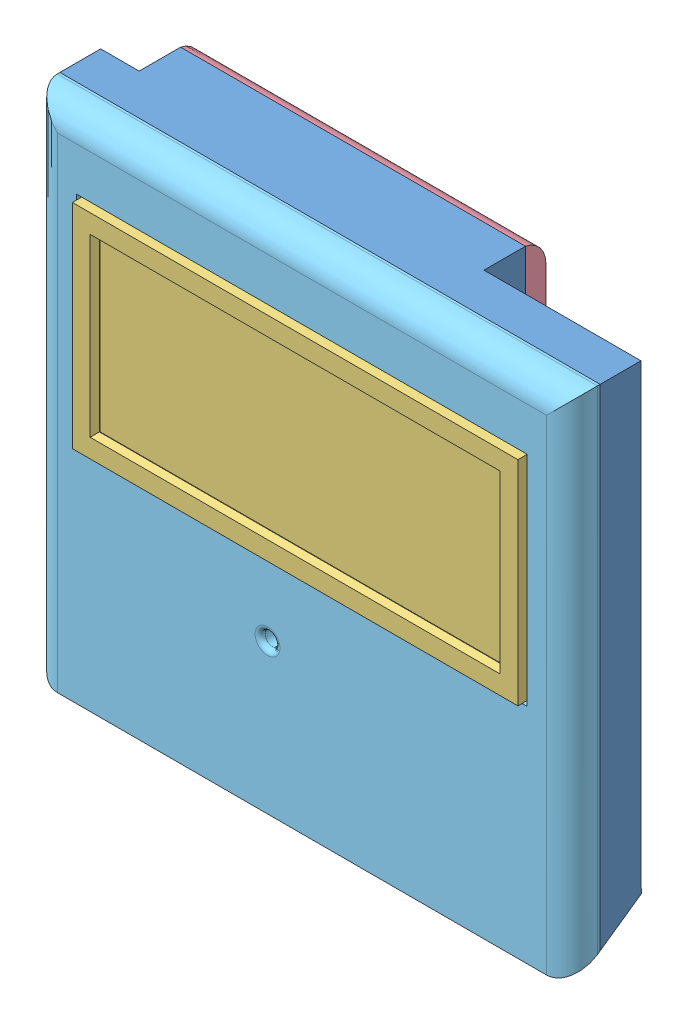
SolidWorks assembly Assem2, configuration Default. Lengths in mm.
Overall size (879.81 203.75 39.02).
7 component instances, 7 part files, 12 mates.
Components (placement in the parent):
- middle-1: middle [Default] at (-126.7138 -34.7069 38.7563) size (105.87 96.14 16.13)
- PCB-1: PCB [Default] at (-122.7138 -30.7069 38.7663) size (255.19 160.09 12.72)
- LCD-2: LCD [Default] at (-130.2538 -17.5769 50.8863) size (765.52 168.67 15.05)
- back-1: back [Default] at (-124.8566 -10.3763 34.7563) x (1 0 0) z (0 -1 0) size (68.96 18.07 84.84)
- Front-1: Front [Default] at (-97.2484 -1.8747 58.8863) x (1 0 0) z (0 1 0) size (105.87 7.85 99.99)
- ResetButton-1: ResetButton [Default] at (-122.7138 42.3331 42.2163) x (1 0 0) z (0 -1 0) size (10.17 4.88 5)
- GPS-1: GPS [Default] at (-73.4443 33.5217 42.1998) x (0 -1 0) z (0 0 1) size (34.65 8.27 6.52)
Mates (geometry in assembly coordinates):
- Coincident2: coincident anti-aligned: plane of middle-1 through (-126.7138 -34.7069 40.3863) normal (0 0 -1); plane of PCB-1 through (-122.7138 -30.7069 40.3863) normal (0 0 1)
- Coincident3: coincident anti-aligned: plane of middle-1 through (-122.7138 43.3331 50.8863) normal (0 -1 0); plane of PCB-1 through (-122.7138 43.3331 40.3863) normal (0 1 0)
- Coincident4: coincident anti-aligned: plane of middle-1 through (-63.1438 43.3331 50.8863) normal (-1 0 0); plane of PCB-1 through (-63.1438 -30.7069 40.3863) normal (1 0 0)
- Coincident8: coincident aligned: plane of PCB-1 through (-81.2138 41.1631 47.9263) normal (0 1 0); plane of LCD-2 through (-81.2138 41.1631 48.3363) normal (0 1 0)
- Coincident9: coincident aligned: plane of PCB-1 through (-81.2138 41.1631 47.9263) normal (1 0 0); plane of LCD-2 through (-81.2138 41.1631 48.3363) normal (1 0 0)
- Coincident10: coincident anti-aligned: plane of middle-1 through (-126.7138 -34.7069 50.8863) normal (0 0 1); plane of LCD-2 through (-130.2538 -17.5769 50.8863) normal (0 0 -1)
- Coincident12: coincident anti-aligned: plane of middle-1 through (-126.7138 -34.7069 38.7563) normal (0 0 -1); plane of back-1 through (-124.8566 -10.3763 38.7563) normal (0 0 1)
- Coincident13: coincident aligned: plane of middle-1 through (-126.7138 -34.7069 50.8863) normal (-1 0 0); plane of back-1 through (-126.7138 47.3331 38.7563) normal (-1 0 0)
- Coincident14: coincident aligned: line of middle-1 through (-59.1438 47.3331 38.7563) axis (-1 0 0); line of back-1 through (-59.1438 47.3331 38.7563) axis (-1 0 0)
- Coincident15: coincident anti-aligned: plane of middle-1 through (-126.7138 -34.7069 54.8863) normal (0 0 1); plane of Front-1 through (-97.2484 -1.8747 54.8863) normal (0 0 -1)
- Concentric1: concentric aligned: circle of middle-1; circle of ResetButton-1
- Coincident18: coincident anti-aligned: plane of middle-1 through (-122.7138 43.3331 50.8863) normal (1 0 0); plane of ResetButton-1 through (-122.7138 37.3331 42.2163) normal (-1 0 0)
